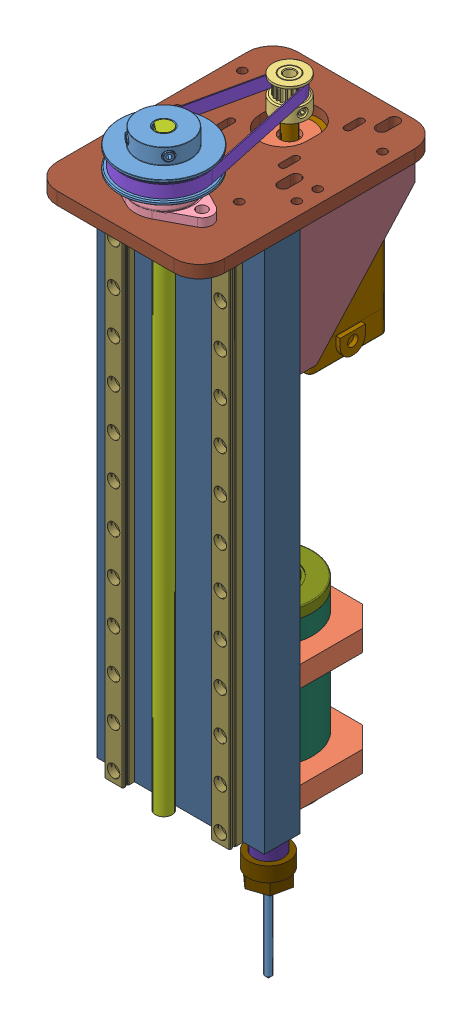
SolidWorks assembly Eje_Z, configuration Predeterminado. Lengths in mm.
Overall size (80 377.42 121.42).
36 component instances, 27 part files, 40 mates.
Components (placement in the parent):
-  GT2_60T_8_6-1:  GT2_60T_8_6 [Default] at (40 277.85 25) x (-0.604715 0 0.796442) z (0 -1 0) size (42 42 18)
-  Nema 17HS4401-S-1:  Nema 17HS4401-S [Varsayılan] at (40.1 209.8 -34.9999) x (0 0 1) z (0 1 0) size (42 48 63.23)
- Correa_158-1: Correa_158 [Predeterminado] at (40 274.85 25) x (0.002632 0 -0.999997) z (0 -1 0) size (63.95 38.7 6) (hidden)
- GT2_20T-1: GT2_20T [Конфигурация1] at (40.1 261.4 -34.9999) x (0 1 0) z (0.17538 0 -0.984501) size (16 16 16)
- KFL08-1: KFL08 [Varsayılan] at (40 256 25) size (46.5 11.35 27)
  - Copia de FLANGE-1: Copia de FLANGE [Default] at origin size (46.5 8.5 27)
  - Copia de BEARING-1: Copia de BEARING [Default] at (0 4 0) x (1 0 0) z (0 -1 0) size (22 22 10.85)
  - socket set screw cone point_am-1: socket set screw cone point_am [B18.3.6M - M2.5 x 0.45 x 2 Hex Socket Cone Pt. SS --S] at (0 9.425 5.45) x (0 0 -1) z (1 0 0) size (2 2.5 2.5)
  - socket set screw cone point_am-2: socket set screw cone point_am [B18.3.6M - M2.5 x 0.45 x 2 Hex Socket Cone Pt. SS --S] at (5.45 9.425 0) x (-1 0 0) z (0 0 -1) size (2 2.5 2.5)
- LeadScrew 8mm x 2mmPitch_eje_Z-1: LeadScrew 8mm x 2mmPitch_eje_Z [Default] at (40 285.35 25) x (-0.604715 0 0.796442) z (0 1 0) size (8 8 283)
- Correa_200z-1: Correa_200z [Predeterminado] at (40 274.85 25) x (0.001667 0 -0.999999) z (0 -1 0) size (85.95 38.7 6)
- Stepper motor NEMA 23HS7430-1: Stepper motor NEMA 23HS7430 [По умолчанию] at (40.1 250 -34.9999) x (1 0 0) z (0 -1 0) size (58.4 56.4 95.6)
- Placa_Motor-1: Placa_Motor [Predeterminado] at origin size (80 250 18)
- Soporte_motor_Z-1: Soporte_motor_Z [Predeterminado] at (80 256 -67) x (0 0 1) z (0 -1 0) size (115 80 6)
- MGN9_250mm-1: MGN9_250mm [Predeterminado] at (65.5 250 20.1943) x (1 0 0) z (0 -1 0) size (9 6.61 250)
- MGN9_250mm-2: MGN9_250mm [Predeterminado] at (14.5 0 20.1943) x (-1 0 0) z (0 1 0) size (9 6.61 250)
- escuadra2^Eje_Z-1: escuadra2^Eje_Z [Predeterminado] at (80 250 0) x (0 0 -1) z (-1 0 0) size (55 60 10) (virtual)
-  escuadra3^Eje_Z-1:  escuadra3^Eje_Z [Predeterminado] at (0 250 0) x (0 -1 0) z (1 0 0) size (60 55 10) (virtual)
- Spindle-1: Spindle [Predeterminado] at (40 -4.5749 -25) x (-0.99895 0 0.045814) z (0 1 0) size (62.23 57.81 175)
  - cuerpo-1: cuerpo [Predeterminado] at origin size (42 42 74)
  - tapa_lado_broca-1: tapa_lado_broca [Predeterminado] x (0.85047 0.526023 0) z (0 0 -1) size (42 42 6.5)
  - tapa_lado_broca-2: tapa_lado_broca [Predeterminado] at (0 0 74) x (-0.987096 0.160131 0) z (0 0 1) size (42 42 6.5)
  - eje-1: eje [Predeterminado] at (0 0 -47.5) x (0.653715 0.756741 0) z (0.756741 -0.653715 0) size (16 135 16)
  - tuerca-1: tuerca [Predeterminado] at (0 0 -34.5) x (-0.923728 -0.383049 0) z (0 0 -1) size (19 19 13)
  - broca-1: broca [Predeterminado] at (0 0 -47.5) x (-0.798235 0.602346 0) z (0 0 -1) size (3.25 3.25 40)
  - soporte-1: soporte [Predeterminado] at (0 0 4.5749) x (0.99895 -0.045814 0) z (0 0 1) size (60 50 10)
  - soporte-2: soporte [Predeterminado] at (0 0 54.5749) x (0.99895 -0.045814 0) z (0 0 1) size (60 50 10)
- Dremel^Eje_Z-1: Dremel^Eje_Z [Predeterminado] at (-50.7875 30.4958 -53.4755) x (0 0 -1) z (1 0 0) size (67.03 292.5 75.38) (hidden, virtual)
  - Dremel Mount^Dremel_Eje_Z-1: Dremel Mount^Dremel_Eje_Z [Default] at (-15.3755 -40.4958 90.4875) size (65.88 90.49 75.38) (virtual)
  - Dremel-1: Dremel [Default] at (-161.576 276.599 217.1061) x (0 0 -1) z (0 -1 0) size (52.6 55.93 292.5)
    - Copia de Body-1: Copia de Body [Default] at (126.6186 146.2005 330.5948) size (52.6 54 276.75)
    - Copia de ON Switch-1: Copia de ON Switch [Default] at (126.6186 166.7005 254.5948) x (0 0 -1) z (1 0 0) size (26 4 13)
    - Copia de Chuck-1: Copia de Chuck [Default] at (126.6186 146.2005 330.5948) x (-0.889361 -0.457206 0) z (0.457206 -0.889361 0) size (15.2 22.5 15.2)
    - Copia de Lock Switch-1: Copia de Lock Switch [Default] at (126.6186 165.7005 287.5948) x (0.5 0 -0.866025) z (0.866025 0 0.5) size (9.54 9.43 8.53)
- LD42WS-1: LD42WS [Predeterminado] at (-165.24 10.0665 -11.4443) x (0 -1 0) z (1 0 0) size (205.24 62 52) (hidden)
  - Spindle-2: Spindle [Default] at (-66.9335 24.5557 205.24) size (205.24 62 52)
Mates (geometry in assembly coordinates):
- Coincidente10: coincident anti-aligned: plane of Correa_158-1 through (40 268.85 25) normal (0 -1 0); plane of GT2_20T-1 through (40.1 268.85 -34.9999) normal (0 1 0)
- Coincidente22: coincident anti-aligned: plane of Placa_Motor-1 through (0 250 18) normal (0 1 0); plane of Soporte_motor_Z-1 through (80 250 -67) normal (0 -1 0)
- Coincidente23: coincident aligned: plane of Placa_Motor-1 through (0 0 18) normal (-1 0 0); plane of Soporte_motor_Z-1 through (0 250 -67) normal (-1 0 0)
- Coincidente26: coincident anti-aligned: plane of KFL08-1/Copia de FLANGE-1 through (58.25 256 25) normal (0 -1 0); plane of Soporte_motor_Z-1 through (80 256 -67) normal (0 1 0)
- Concéntrica8: concentric anti-aligned: cylinder of KFL08-1/Copia de BEARING-1 through (40 256.5 25) axis (0 -1 0) radius 4; cylinder of Soporte_motor_Z-1 through (40 250 25) axis (0 1 0) radius 6
- Concéntrica9: concentric aligned: cylinder of KFL08-1/Copia de FLANGE-1 through (58.25 260 25) axis (0 1 0) radius 2.5; cylinder of Soporte_motor_Z-1 through (58.25 250 25) axis (0 1 0) radius 1.625
- Coincidente31: coincident anti-aligned: plane of  Nema 17HS4401-S-1 through (40.1 250 -34.9999) normal (0 1 0); plane of Soporte_motor_Z-1 through (80 250 -67) normal (0 -1 0)
- Tangente2: tangent anti-aligned: cylinder of  Nema 17HS4401-S-1 through (40.1 252 -34.9999) axis (0 -1 0) radius 11; plane of Soporte_motor_Z-1 through (51.1 250 -38) normal (-1 0 0)
- Distancia2: distance = 7 mm: plane of Placa_Motor-1 through (0 0 18) normal (0 0 1); cylinder of Soporte_motor_Z-1 through (40 250 25) axis (0 1 0) radius 6
- Concéntrica10: concentric anti-aligned: cylinder of KFL08-1/Copia de BEARING-1 through (40 256.5 25) axis (0 -1 0) radius 4; cylinder of LeadScrew 8mm x 2mmPitch_eje_Z-1 through (40 2.35 25) axis (0 1 0) radius 4
- Concéntrica11: concentric aligned: cylinder of  GT2_60T_8_6-1 through (40 247.85 25) axis (0 1 0) radius 4; cylinder of LeadScrew 8mm x 2mmPitch_eje_Z-1 through (40 2.35 25) axis (0 1 0) radius 4
- Coincidente33: coincident anti-aligned: plane of  GT2_60T_8_6-1 through (40 267.35 25) normal (0 -1 0); plane of KFL08-1/Copia de BEARING-1 through (40 267.35 29.3) normal (0 1 0)
- Coincidente34: coincident aligned: plane of  GT2_60T_8_6-1 through (40 285.35 25) normal (0 1 0); plane of LeadScrew 8mm x 2mmPitch_eje_Z-1 through (40 285.35 25) normal (0 1 0)
- Paralelo10: parallel aligned: plane of  GT2_60T_8_6-1 through (32.1387 281.6 35.3537) normal (-0.604715 0 0.796442); plane of LeadScrew 8mm x 2mmPitch_eje_Z-1 through (42.4045 275.35 30.5924) normal (-0.604715 0 0.796442)
- Concéntrica12: concentric anti-aligned: cylinder of  Nema 17HS4401-S-1 through (40.1 273 -34.9999) axis (0 -1 0) radius 2.5; cylinder of GT2_20T-1 through (40.1 261.4 -34.9999) axis (0 1 0) radius 2.5
- Coincidente36: coincident anti-aligned: plane of  GT2_60T_8_6-1 through (40 268.85 25) normal (0 1 0); plane of Correa_158-1 through (40 268.85 25) normal (0 -1 0)
- Concéntrica13: concentric anti-aligned: cylinder of  GT2_60T_8_6-1 through (40 285.35 25) axis (0 -1 0) radius 12.5; cylinder of Correa_158-1 through (40 268.85 25) axis (0 1 0) radius 18.85
- Coincidente45: coincident anti-aligned: plane of Placa_Motor-1 through (0 0 0) normal (0 0 -1); plane of Spindle-1/soporte-1 through (10 10 0) normal (0 0 1)
- Distancia3: distance = 10 mm aligned: plane of Spindle-1/soporte-1 through (70 10 0) normal (1 0 0); plane of Placa_Motor-1 through (80 0 18) normal (1 0 0)
- Coincidente47: coincident aligned: plane of Placa_Motor-1 through (0 0 18) normal (0 -1 0); plane of Spindle-1/soporte-1 through (40 0 -25) normal (0 -1 0)
- Coincidente48: coincident anti-aligned: plane of Placa_Motor-1 through (0 0 0) normal (0 0 -1); plane of Dremel^Eje_Z-1/Dremel Mount^Dremel_Eje_Z-1 through (39.7 71.7562 0) normal (0 0 1)
- Distancia5: distance = 10 mm aligned: plane of Placa_Motor-1 through (0 0 18) normal (0 -1 0); plane of Dremel^Eje_Z-1/Dremel Mount^Dremel_Eje_Z-1 through (39.7 -10 -38.1) normal (0 -1 0)
- Distancia6: distance = 27 mm aligned: plane of Placa_Motor-1 through (0 0 18) normal (-1 0 0); plane of Dremel^Eje_Z-1/Dremel Mount^Dremel_Eje_Z-1 through (27 71.7562 -9.525) normal (-1 0 0)
- Coincidente49: coincident aligned: plane of Placa_Motor-1 through (0 0 18) normal (0 -1 0); plane of LD42WS-1/Spindle-2 through (40 0 -36) normal (0 -1 0)
- Coincidente50: coincident anti-aligned: plane of Placa_Motor-1 through (0 0 0) normal (0 0 -1); plane of LD42WS-1/Spindle-2 through (66 0 0) normal (0 0 1)
- Distancia7: distance = 14 mm aligned: plane of Placa_Motor-1 through (0 0 18) normal (-1 0 0); plane of LD42WS-1/Spindle-2 through (14 0 -10) normal (-1 0 0)
- Coincidente51: coincident anti-aligned: plane of  GT2_60T_8_6-1 through (40 268.85 25) normal (0 1 0); plane of Correa_200z-1 through (40 268.85 25) normal (0 -1 0)
- Concéntrica14: concentric anti-aligned: cylinder of  GT2_60T_8_6-1 through (40 285.35 25) axis (0 -1 0) radius 12.5; cylinder of Correa_200z-1 through (40 268.85 25) axis (0 1 0) radius 19.35
- Paralelo11: parallel aligned: plane of  Nema 17HS4401-S-1 through (22.6 219.3 -55.9999) normal (0 0 -1); plane of Soporte_motor_Z-1 through (80 250 -67) normal (0 0 -1)
- Concéntrica15: concentric anti-aligned: cylinder of GT2_20T-1 through (40.1 261.4 -34.9999) axis (0 -1 0) radius 8; cylinder of Correa_200z-1 through (40.1 268.85 -34.9999) axis (0 1 0) radius 6.6
- Coincidente52: coincident aligned: line of Placa_Motor-1 through (250 80 0) axis (0 0 1); line of escuadra2^Eje_Z-1 through (60 80 190) axis (0 0 1)
- Coincidente53: coincident anti-aligned: line of Soporte_motor_Z-1 through (80 250 -55) axis (0 0 1); line of escuadra2^Eje_Z-1 through (80 250 0) axis (0 0 -1)
- Coincidente55: coincident aligned: line of Placa_Motor-1 through (250 0 250) axis (0 0 -1); line of  escuadra3^Eje_Z-1 through (0 250 0) axis (0 -1 0)
- Coincidente56: coincident anti-aligned: line of Soporte_motor_Z-1 through (0 250 36) axis (0 0 -1); line of  escuadra3^Eje_Z-1 through (0 250 -55) axis (0 0 1)
- Concéntrica16: concentric anti-aligned: cylinder of GT2_20T-1 through (40.1 261.4 -34.9999) axis (0 1 0) radius 2.5; cylinder of Stepper motor NEMA 23HS7430-1 through (40.1 270.6 -34.9999) axis (0 -1 0) radius 3.175
- Paralelo12: parallel aligned: plane of Soporte_motor_Z-1 through (80 250 -67) normal (0 0 -1); plane of Stepper motor NEMA 23HS7430-1 through (11.9 240 -63.1999) normal (0 0 -1)
- Coincidente67: coincident aligned: line of Placa_Motor-1 through (61 0 17) axis (1 0 0); line of MGN9_250mm-1 through (63.9 0 17) axis (1 0 0)
- Coincidente68: coincident: moEndPointRef_w of MGN9_250mm-1; line of Placa_Motor-1 through (61 0 17) axis (0 0 1)
- Coincidente69: coincident: line of Placa_Motor-1 through (0 0 17) axis (1 0 0); line of MGN9_250mm-2 through (2.4269 0 17) axis (1 0 0)
- Coincidente70: coincident: line of Placa_Motor-1 through (19 0 17) axis (0 0 1); line of MGN9_250mm-2 through (10.4 0 17) axis (0 1 0)
